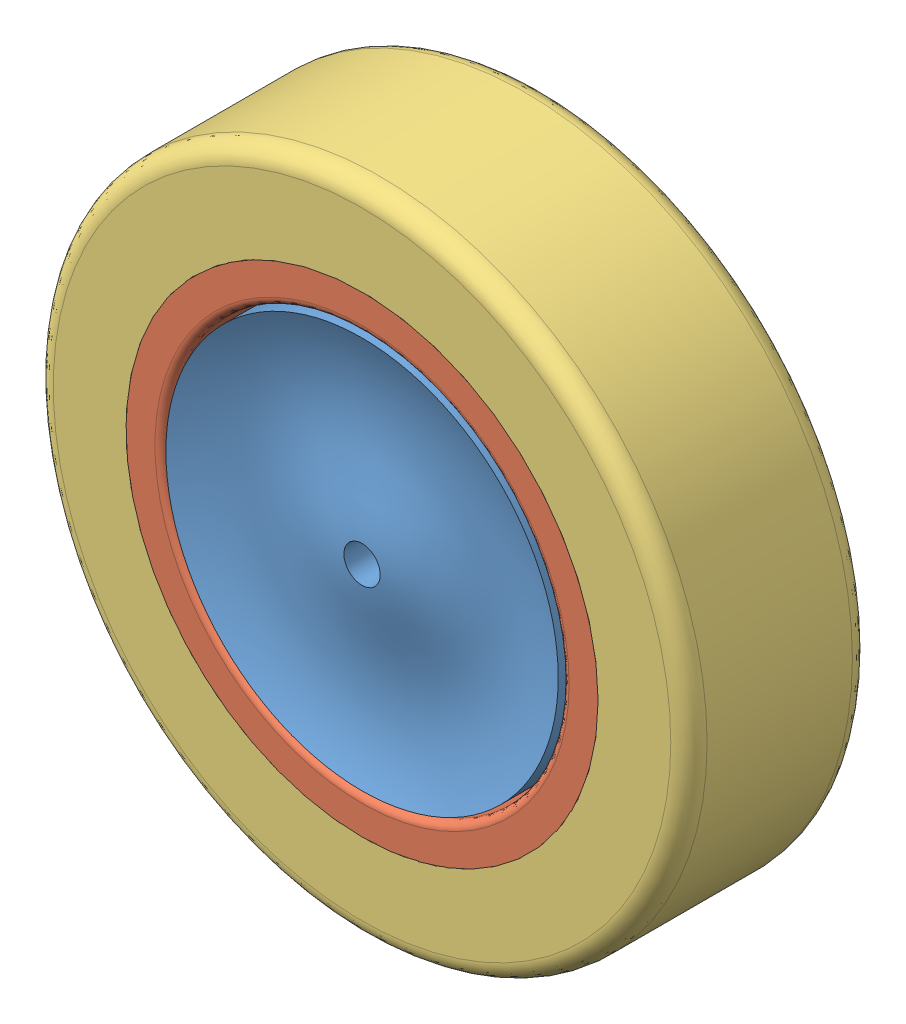
SolidWorks assembly Castor Wheel, configuration Default. Lengths in mm.
Overall size (180 180 79.3).
3 component instances, 3 part files, 4 mates.
Components (placement in the parent):
- Inside 2-1: Inside 2 [Default] at origin size (110.08 110.08 79.3)
- Inside 1-1: Inside 1 [Default] at origin size (130 130 50)
- Rubber Wheel-2: Rubber Wheel [Default] at (0 45 25) x (0 0 1) z (-1 0 0) size (50 180 180)
Mates (geometry in assembly coordinates):
- Coincident1: coincident: plane of Inside 2-1 through (0 0 0) normal (0 0 1); plane of Inside 1-1 through (0 0 0) normal (0 0 1)
- Concentric3: concentric: cylinder of Inside 2-1 through (0 0 50) axis (0 0 -1) radius 54; cylinder of Inside 1-1 through (0 0 0) axis (0 0 1) radius 55
- Concentric5: concentric: cylinder of Inside 1-1 through (0 0 50) axis (0 0 -1) radius 65; cylinder of Rubber Wheel-2 through (0 0 0) axis (0 0 1) radius 65
- Coincident12: coincident: circle of Inside 1-1; plane of Rubber Wheel-2 through (0 0 50) normal (0 0 1)
